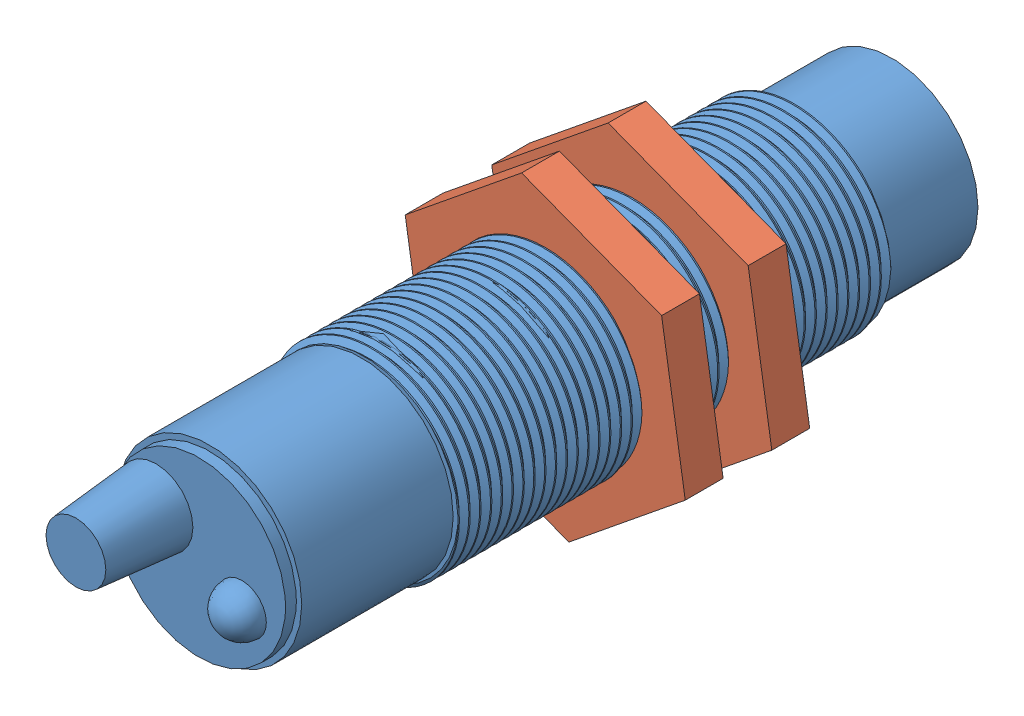
SolidWorks assembly LJ18A3, configuration Default. Lengths in mm.
Overall size (25.89 27.37 71.4).
6 component instances, 3 part files, 0 mates.
Components (placement in the parent):
- LJ18A3.step-1: LJ18A3.step [Default] at origin size (30 30 71.4)
  - Sensor.step-1: Sensor.step [Default] at origin size (18.25 18.25 71.4)
  - Nut.step-1: Nut.step [Default] at (69.0679 5.4432 19.5) size (25.89 27.37 3.53)
  - Spacer.step-1: Spacer.step [Default] at (163.1041 9.6725 17.5) size (30 30 1) (hidden)
  - Nut.step-2: Nut.step [Default] at (69.0679 5.4432 11.5) size (25.89 27.37 3.53)
  - Spacer.step-2: Spacer.step [Default] at (163.1041 9.6725 16) size (30 30 1) (hidden)
